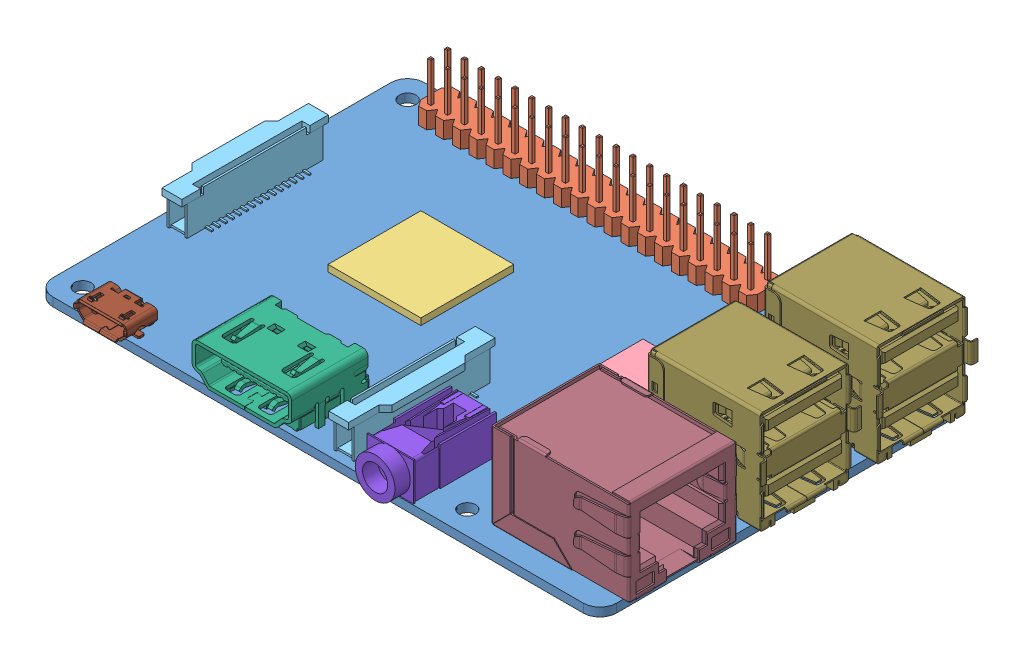
SolidWorks assembly RaspberryPi2 нью, configuration Default. Lengths in mm.
Overall size (89.62 18.75 58.3).
15 component instances, 13 part files, 43 mates.
Components (placement in the parent):
- Mainboard2-1: Mainboard2 [Default] at origin size (85 1.3 56)
- GPIO-1: GPIO [Default] at (-11.37 0 -24.5) x (0 0 1) z (-1 0 0) size (5 11.5 50.8)
- Processor-1: Processor [Default] at (-15.5 0 -3) x (0 0 1) z (-1 0 0) size (14 1 14)
- GPU-1: GPU [Default] at (15.25 0 -5.75) x (0 0 1) z (-1 0 0) size (9.1 1 9.1)
- CameraAssembly-4: CameraAssembly [Default] at (10.0885 -2.9159 16.55) x (-1 0 0) z (0 0 -1) size (5 5.5 22.1)
- CameraAssembly-3: CameraAssembly [Default] at (-46.3885 -2.9159 0) size (5 5.5 22.1)
- hdmi-1: hdmi [Default] at (-10.2 0.27 29.3) size (15.14 8.38 12.15)
- RAM-1: RAM [Default] at (0.5 -2.3 -6) x (0 0 1) z (-1 0 0) size (12 1 12)
- Audio-1: Audio [Default] at (10.9 0.15 21.75) size (7 6 14.8)
- MicroSDSocket-1: MicroSDSocket [Default] at (-34.5 -1.3 -0.7) x (0 0 -1) z (-1 0 0) size (13 1.3 14)
- MicroSD-1: MicroSD [Default] at (-37 -2.3 0.1) x (0 0 1) z (-1 0 0) size (11 1 15)
- micro USB2-1: micro USB2 [Default] at (-17.2704 -5.0969 44.9026) size (7.99 2.94 5.43)
- usb double-1: usb double [Default] at (30.38 -0.09 -18.85) x (0 0 -1) z (1 0 0) size (15.6 18.75 17.92)
- usb double-2: usb double [Default] at (30.38 -0.09 -1.25) x (0 0 -1) z (1 0 0) size (15.6 18.75 17.92)
- RJ45-LED-1: RJ45-LED [Default] at (34.11 7.4 17.348) x (1 0 0) z (0 -1 0) size (20.75 17.99 14.09)
Mates (geometry in assembly coordinates):
- Coincidente19: coordinate: point of Mainboard2-1; point of assembly
- Distanza16: distance = 2.3 mm aligned: plane of Audio-1 through (10.9 6 30.3) normal (0 0 1); plane of Mainboard2-1 through (-40 -1.3 28) normal (0 0 1)
- Distanza17: distance = 28.1 mm aligned: plane of Audio-1 through (14.4 0.15 28) normal (1 0 0); plane of Mainboard2-1 through (42.5 -1.3 25.5) normal (1 0 0)
- Distanza20: distance = 6.5 mm aligned: plane of hdmi-1 through (-4.6 6.5 17.85) normal (0 1 0); plane of Mainboard2-1 through (40 0 25.5) normal (0 1 0)
- Distanza27: distance = 0.1 mm anti-aligned: plane of MicroSD-1 through (-37.1747 -2.3 0.1936) normal (0 -1 0); plane of MicroSDSocket-1 through (-34.5 -2.4 -0.7) normal (0 1 0)
- Coincidente39: coincident anti-aligned: plane of MicroSDSocket-1 through (-27.5 -1.3 5.6) normal (0 0 -1); plane of MicroSD-1 through (-44.5 -2.3 5.6) normal (0 0 1)
- Distanza28: distance = 3 mm aligned: plane of MicroSD-1 through (-44.5 -2.3 -5.4) normal (-1 0 0); plane of MicroSDSocket-1 through (-41.5 -1.3 5.8) normal (-1 0 0)
- Coincidente41: coincident anti-aligned: plane of Mainboard2-1 through (40 -1.3 25.5) normal (0 -1 0); plane of MicroSDSocket-1 through (-34.5 -1.3 -0.7) normal (0 1 0)
- Distanza29: distance = 1 mm aligned: plane of MicroSDSocket-1 through (-41.5 -1.3 5.8) normal (-1 0 0); plane of Mainboard2-1 through (-42.5 -1.3 -25.5) normal (-1 0 0)
- Distanza30: distance = 20.8 mm aligned: plane of MicroSDSocket-1 through (-41.5 -1.3 -7.2) normal (0 0 -1); plane of Mainboard2-1 through (40 -1.3 -28) normal (0 0 -1)
- Coincidente44: coincident anti-aligned: plane of Mainboard2-1 through (40 0 25.5) normal (0 1 0); plane of GPIO-1 through (-11.37 0 -24.5) normal (0 -1 0)
- Distanza31: distance = 7 mm aligned: plane of GPIO-1 through (-35.5 0 -26) normal (-1 0 0); plane of Mainboard2-1 through (-42.5 -1.3 -25.5) normal (-1 0 0)
- Distanza32: distance = 1 mm aligned: plane of GPIO-1 through (-33.63 0 -27) normal (0 0 -1); plane of Mainboard2-1 through (40 -1.3 -28) normal (0 0 -1)
- Coincidente47: coincident anti-aligned: plane of Mainboard2-1 through (40 0 25.5) normal (0 1 0); plane of Processor-1 through (-15.5 0 -3) normal (0 -1 0)
- Distanza33: distance = 18 mm aligned: plane of Processor-1 through (-8.5 0 -10) normal (0 0 -1); plane of Mainboard2-1 through (40 -1.3 -28) normal (0 0 -1)
- Distanza34: distance = 20 mm aligned: plane of Processor-1 through (-22.5 0 -10) normal (-1 0 0); plane of Mainboard2-1 through (-42.5 -1.3 -25.5) normal (-1 0 0)
- Coincidente50: coincident anti-aligned: plane of Mainboard2-1 through (40 -1.3 25.5) normal (0 -1 0); plane of RAM-1 through (0.5 -1.3 -6) normal (0 1 0)
- Distanza35: distance = 16 mm aligned: plane of RAM-1 through (6.5 -2.3 -12) normal (0 0 -1); plane of Mainboard2-1 through (40 -1.3 -28) normal (0 0 -1)
- Distanza36: distance = 37 mm aligned: plane of RAM-1 through (-5.5 -2.3 -12) normal (-1 0 0); plane of Mainboard2-1 through (-42.5 -1.3 -25.5) normal (-1 0 0)
- Coincidente53: coincident anti-aligned: plane of Mainboard2-1 through (40 0 25.5) normal (0 1 0); plane of GPU-1 through (15.25 0 -5.75) normal (0 -1 0)
- Distanza37: distance = 18 mm aligned: plane of GPU-1 through (19.5 0 -10) normal (0 0 -1); plane of Mainboard2-1 through (40 -1.3 -28) normal (0 0 -1)
- Distanza38: distance = 23 mm aligned: plane of GPU-1 through (19.5 0 -1.5) normal (1 0 0); plane of Mainboard2-1 through (42.5 -1.3 25.5) normal (1 0 0)
- Distanza39: distance = 1.3 mm aligned: plane of hdmi-1 through (-28.801 6 29.3) normal (0 0 1); plane of Mainboard2-1 through (-40 -1.3 28) normal (0 0 1)
- Distanza40: distance = 24.8 mm aligned: plane of hdmi-1 through (-17.7 18.8639 17.85) normal (-1 0 0); plane of Mainboard2-1 through (-42.5 -1.3 -25.5) normal (-1 0 0)
- Tangente2: tangent anti-aligned: plane of Mainboard2-1 through (40 0 25.5) normal (0 1 0); cylinder of Audio-1 through (10.9 3 29.15) axis (0 0 -1) radius 3
- Distanza43: distance = 2.6 mm anti-aligned: plane of micro USB2-1 through (-34.95 2.6 24.1941) normal (0 -1 0); plane of Mainboard2-1 through (40 0 25.5) normal (0 1 0)
- Distanza44: distance = 1.3 mm anti-aligned: cylinder of micro USB2-1 through (-29.25 0.0937 29.31) axis (-1 0 0) radius 0.01; plane of Mainboard2-1 through (-40 -1.3 28) normal (0 0 1)
- Distanza45: distance = 7 mm anti-aligned: plane of micro USB2-1 through (-35.5 1.3036 24.1941) normal (1 0 0); plane of Mainboard2-1 through (-42.5 -1.3 -25.5) normal (-1 0 0)
- Distanza46: distance = 15.5 mm aligned: plane of usb double-1 through (33.3225 15.5 -40.1817) normal (0 1 0); plane of Mainboard2-1 through (40 0 25.5) normal (0 1 0)
- Coincidente61: coincident aligned: plane of usb double-1 through (33.3225 15.5 -40.1817) normal (0 1 0); plane of usb double-2 through (33.3225 15.5 -22.5817) normal (0 1 0)
- Coincidente63: coincident aligned: plane of usb double-1 through (44.5 -0.09 -18.85) normal (1 0 0); plane of usb double-2 through (44.5 -0.09 -1.25) normal (1 0 0)
- Distanza47: distance = 2.5 mm aligned: plane of usb double-1 through (33.3225 0.4896 -25.5) normal (0 0 -1); plane of Mainboard2-1 through (40 -1.3 -28) normal (0 0 -1)
- Distanza48: distance = 4.3 mm anti-aligned: plane of usb double-2 through (33.3225 0.4896 -7.9) normal (0 0 -1); plane of usb double-1 through (33.3225 43.1529 -12.2) normal (0 0 1)
- Distanza49: distance = 14 mm aligned: plane of RJ45-LED-1 through (44.36 14 25.248) normal (0 1 0); plane of Mainboard2-1 through (40 0 25.5) normal (0 1 0)
- Distanza50: distance = 2 mm aligned: plane of usb double-2 through (44.5 -0.09 -1.25) normal (1 0 0); plane of Mainboard2-1 through (42.5 -1.3 25.5) normal (1 0 0)
- Coincidente68: coincident aligned: plane of usb double-2 through (44.36 -0.09 -1.25) normal (1 0 0); plane of RJ45-LED-1 through (44.36 0.8 25.248) normal (1 0 0)
- Distanza51: distance = 2.5 mm aligned: plane of RJ45-LED-1 through (34.11 7.4 25.5) normal (0 0 1); plane of Mainboard2-1 through (-40 -1.3 28) normal (0 0 1)
- Distanza52: distance = 3.2 mm anti-aligned: plane of Audio-1 through (7.4 0.15 15.5) normal (-1 0 0); plane of CameraAssembly-4 through (4.2 0 26.8) normal (1 0 0)
- Distanza53: distance = 1.2 mm aligned: plane of CameraAssembly-4 through (1.2 0 26.8) normal (0 0 1); plane of Mainboard2-1 through (-40 -1.3 28) normal (0 0 1)
- Coincidente72: coincident anti-aligned: plane of Mainboard2-1 through (40 0 25.5) normal (0 1 0); plane of CameraAssembly-4 through (2.7 0 16.55) normal (0 -1 0)
- Distanza54: distance = 2 mm aligned: plane of CameraAssembly-3 through (-40.5 0 -10.25) normal (-1 0 0); plane of Mainboard2-1 through (-42.5 -1.3 -25.5) normal (-1 0 0)
- Distanza55: distance = 17.75 mm: plane of CameraAssembly-3 through (-40.5 0 10.25) normal (0 0 1); line of Mainboard2-1 through (-40 0 28) axis (1 0 0)
- Coincidente75: coincident anti-aligned: plane of Mainboard2-1 through (40 0 25.5) normal (0 1 0); plane of CameraAssembly-3 through (-39 0 0) normal (0 -1 0)
